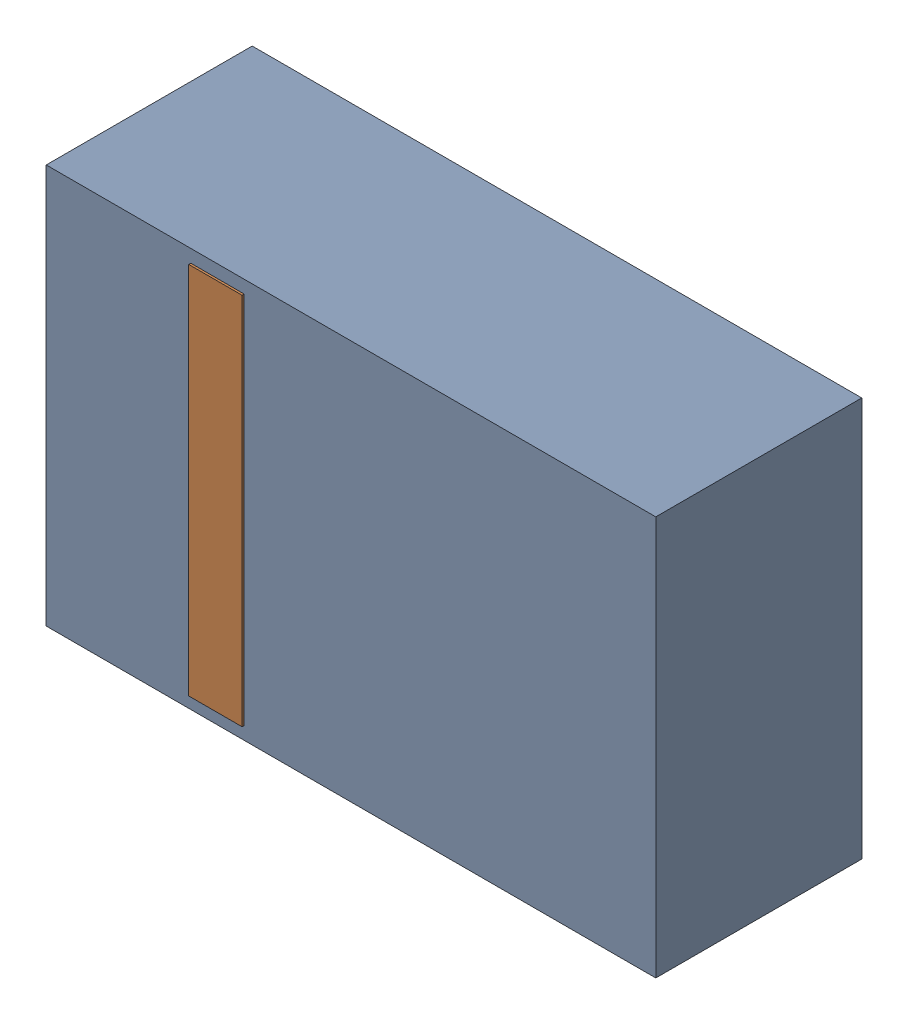
SolidWorks assembly D35, configuration Default. Lengths in mm.
Overall size (2.9 1.9 0.99).
4 component instances, 2 part files, 0 mates.
Components (placement in the parent):
- 905269392-1: 905269392 [Default] at (192.532 71.882 0) size (2.9 1.9 0.98)
  - Extruded_5-1: Extruded_5 [Default] at origin size (2.9 1.9 0.98)
- 905269800-1: 905269800 [Default] at (191.897 71.882 0.95) size (0.25 1.78 0.04)
  - Extruded_6-1: Extruded_6 [Default] at origin size (0.25 1.78 0.04)
